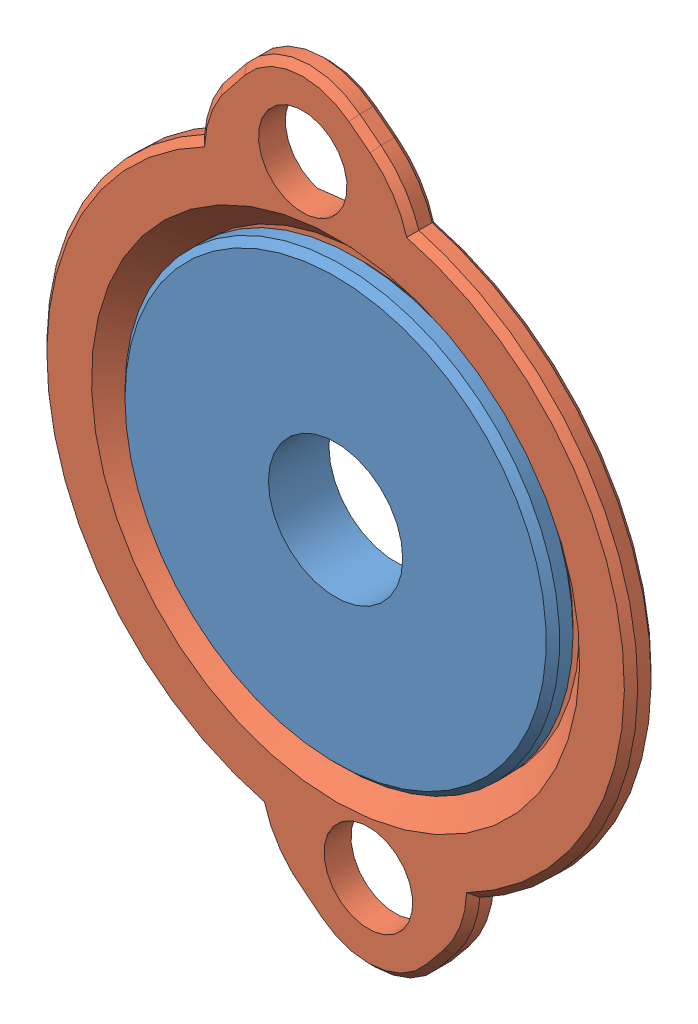
SolidWorks assembly sistema_elevatorio, configuration Default. Lengths in mm.
Overall size (24.97 30.27 3.25).
2 component instances, 2 part files, 2 mates.
Components (placement in the parent):
- fixo-1: fixo [Default] at origin size (16.18 16.18 3.25)
- rotativo-1: rotativo [Default] at (0 0 -1) x (-0.111049 0.993815 0) z (-0.993815 -0.111049 0) size (28 2 22)
Mates (geometry in assembly coordinates):
- Coincident1: coincident anti-aligned: plane of fixo-1 through (8.09 0 -1) normal (0 0 -1); plane of rotativo-1 through (-0.7313 6.5451 -1) normal (0 0 1)
- Concentric1: concentric aligned: cylinder of fixo-1; cylinder of rotativo-1
